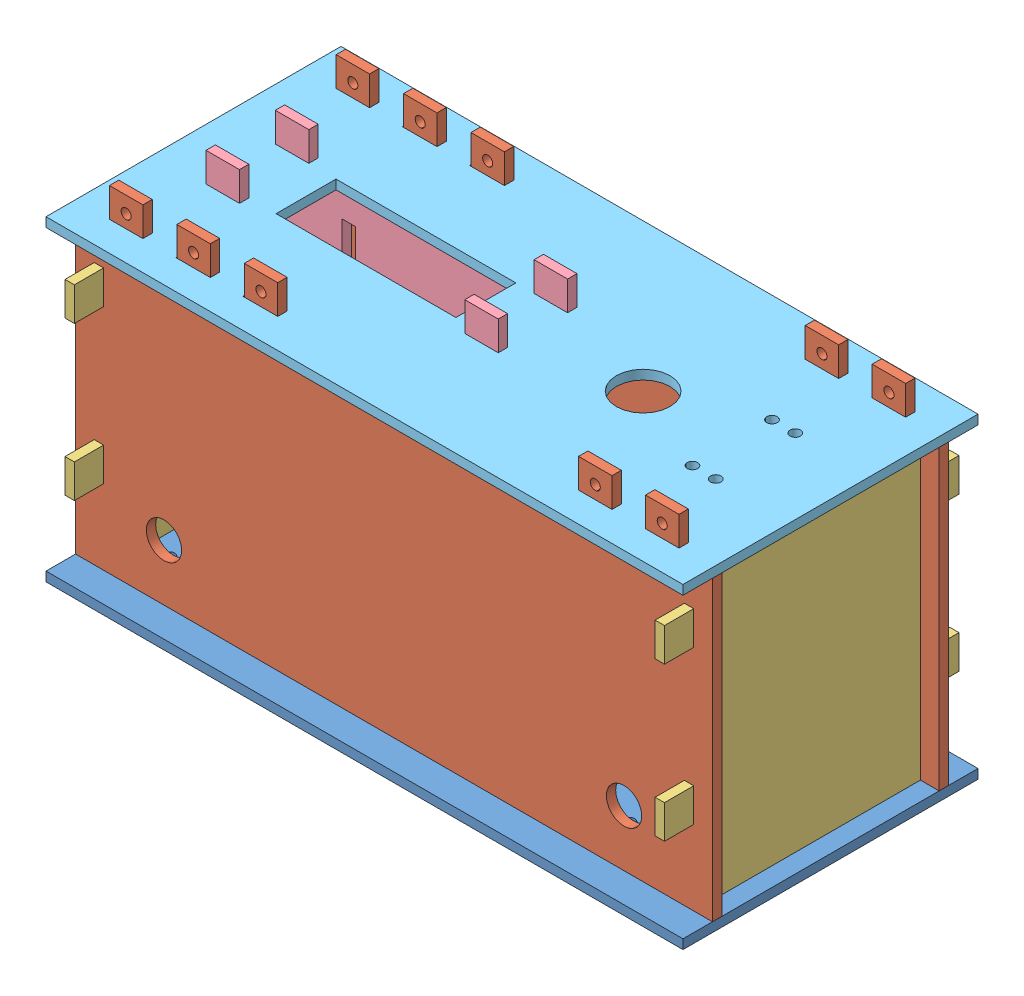
SolidWorks assembly assembly_version_2, configuration Default. Lengths in mm.
Overall size (215.9 127 100).
8 component instances, 5 part files, 23 mates.
Components (placement in the parent):
- bottompanel-1: bottompanel [Default] at (110.0312 77.2247 191.3138) size (215.9 3.17 100)
- sidepanel_copy-1: sidepanel_copy [Default] at (48.6032 164.8752 210.6749) size (215.9 127 3.17)
- sidepanel_copy-2: sidepanel_copy [Default] at (48.6032 164.8752 133.8499) size (215.9 127 3.17)
- innerplates-1: innerplates [Default] at (210.3754 115.845 172.6145) x (0 0 1) z (-1 0 0) size (99.82 100.84 3.17)
- innerplates-2: innerplates [Default] at (7.1754 115.845 175.0954) x (0 0 -1) z (1 0 0) size (99.82 100.84 3.17)
- holder-1: holder [Default] at (52.7197 114.8325 160.4749) size (106.68 127 3.17)
- holder-2: holder [Default] at (52.7197 114.8325 183.9699) size (106.68 127 3.17)
- toppanel-1: toppanel [Default] at (110.0312 181.2396 191.3138) size (215.9 3.17 100)
Mates (geometry in assembly coordinates):
- Coincident2: coincident anti-aligned: plane of bottompanel-1 through (12.1754 77.2247 210.6749) normal (0 0 1); plane of sidepanel_copy-1 through (48.6032 164.8752 210.6749) normal (0 0 -1)
- Coincident3: coincident anti-aligned: plane of bottompanel-1 through (12.1754 77.2247 213.8499) normal (0 0 -1); plane of sidepanel_copy-1 through (48.6032 164.8752 213.8499) normal (0 0 1)
- Coincident4: coincident anti-aligned: plane of bottompanel-1 through (110.0312 80.3997 191.3138) normal (0 1 0); plane of sidepanel_copy-1 through (171.3254 80.3997 213.8499) normal (0 -1 0)
- Coincident5: coincident anti-aligned: plane of bottompanel-1 through (205.3754 77.2247 210.6749) normal (-1 0 0); plane of sidepanel_copy-1 through (205.3754 80.3997 213.8499) normal (1 0 0)
- Coincident6: coincident anti-aligned: plane of bottompanel-1 through (12.1754 77.2247 133.8499) normal (0 0 1); plane of sidepanel_copy-2 through (48.6032 164.8752 133.8499) normal (0 0 -1)
- Coincident7: coincident anti-aligned: plane of bottompanel-1 through (12.1754 77.2247 137.0249) normal (0 0 -1); plane of sidepanel_copy-2 through (48.6032 164.8752 137.0249) normal (0 0 1)
- Coincident8: coincident anti-aligned: plane of bottompanel-1 through (12.1754 77.2247 133.8499) normal (1 0 0); plane of sidepanel_copy-2 through (12.1754 80.3997 137.0249) normal (-1 0 0)
- Coincident9: coincident anti-aligned: plane of bottompanel-1 through (110.0312 80.3997 191.3138) normal (0 1 0); plane of sidepanel_copy-2 through (171.3254 80.3997 137.0249) normal (0 -1 0)
- Coincident10: coincident anti-aligned: plane of sidepanel_copy-1 through (210.3754 169.1396 210.6749) normal (-1 0 0); plane of innerplates-1 through (210.3754 115.845 172.6145) normal (1 0 0)
- Coincident11: coincident anti-aligned: plane of bottompanel-1 through (110.0312 80.3997 191.3138) normal (0 1 0); plane of innerplates-1 through (207.2004 80.3997 123.9449) normal (0 -1 0)
- Coincident12: coincident anti-aligned: plane of sidepanel_copy-2 through (48.6032 164.8752 137.0249) normal (0 0 1); plane of innerplates-1 through (210.3754 157.7897 137.0249) normal (0 0 -1)
- Coincident13: coincident anti-aligned: plane of sidepanel_copy-1 through (7.1754 169.1396 210.6749) normal (1 0 0); plane of innerplates-2 through (7.1754 115.845 175.0954) normal (-1 0 0)
- Coincident14: coincident anti-aligned: plane of bottompanel-1 through (110.0312 80.3997 191.3138) normal (0 1 0); plane of innerplates-2 through (10.3504 80.3997 223.765) normal (0 -1 0)
- Coincident15: coincident anti-aligned: plane of sidepanel_copy-2 through (48.6032 164.8752 137.0249) normal (0 0 1); plane of innerplates-2 through (7.1754 157.7897 137.0249) normal (0 0 -1)
- Coincident16: coincident anti-aligned: plane of bottompanel-1 through (110.0312 80.3997 191.3138) normal (0 1 0); plane of holder-1 through (29.7014 80.3997 160.4749) normal (0 -1 0)
- Coincident17: coincident anti-aligned: plane of bottompanel-1 through (117.4114 77.2247 160.4749) normal (-1 0 0); plane of holder-1 through (117.4114 80.3997 160.4749) normal (1 0 0)
- Coincident18: coincident anti-aligned: plane of bottompanel-1 through (18.3514 77.2247 163.6499) normal (0 0 -1); plane of holder-1 through (52.7197 114.8325 163.6499) normal (0 0 1)
- Coincident19: coincident anti-aligned: plane of bottompanel-1 through (110.0312 80.3997 191.3138) normal (0 1 0); plane of holder-2 through (29.7014 80.3997 183.9699) normal (0 -1 0)
- Coincident20: coincident anti-aligned: plane of bottompanel-1 through (117.4114 77.2247 183.9699) normal (-1 0 0); plane of holder-2 through (117.4114 80.3997 183.9699) normal (1 0 0)
- Coincident21: coincident anti-aligned: plane of bottompanel-1 through (106.0614 77.2247 183.9699) normal (0 0 1); plane of holder-2 through (52.7197 114.8325 183.9699) normal (0 0 -1)
- Coincident22: coincident anti-aligned: plane of sidepanel_copy-2 through (171.3254 181.2396 137.0249) normal (0 1 0); plane of toppanel-1 through (110.0312 181.2396 191.3138) normal (0 -1 0)
- Coincident23: coincident anti-aligned: plane of sidepanel_copy-2 through (48.6032 164.8752 133.8499) normal (0 0 -1); plane of toppanel-1 through (171.3254 181.2396 133.8499) normal (0 0 1)
- Coincident24: coincident anti-aligned: plane of sidepanel_copy-2 through (205.3754 194.3197 137.0249) normal (1 0 0); plane of toppanel-1 through (205.3754 181.2396 133.8499) normal (-1 0 0)
